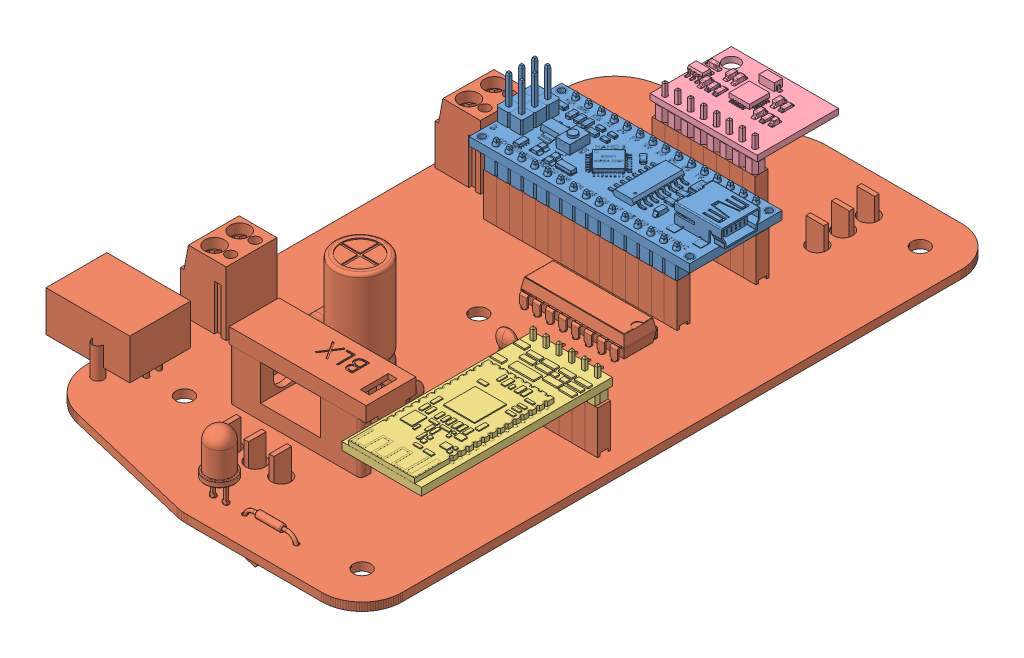
SolidWorks assembly BDT_E_A_23_v01, configuration Valor predeterminado. Lengths in mm.
Overall size (77.11 35.69 126).
4 component instances, 4 part files, 0 mates.
Components (placement in the parent):
- BDT_E_P_30_v01-1: BDT_E_P_30_v01 [Valor predeterminado] at (294.3095 192.4539 -243.1098) size (44.45 18.33 18.2)
- BDT_E_P_27_v01-1: BDT_E_P_27_v01 [Valor predeterminado] at (277.1845 180.5509 -164.2098) x (0 0 -1) z (0 1 0) size (126 77.11 34.65)
- BDT_E_P_28_v01-1: BDT_E_P_28_v01 [Valor predeterminado] at (319.751 193.8939 -207.1932) x (0 0 1) z (-1 0 0) size (37.6 11.44 15.7)
- BDT_E_P_29_v01-1: BDT_E_P_29_v01 [Valor predeterminado] at (300.3291 182.0071 -251.1642) x (-1 0 0) z (0 0 -1) size (21.11 11.18 16.13)
